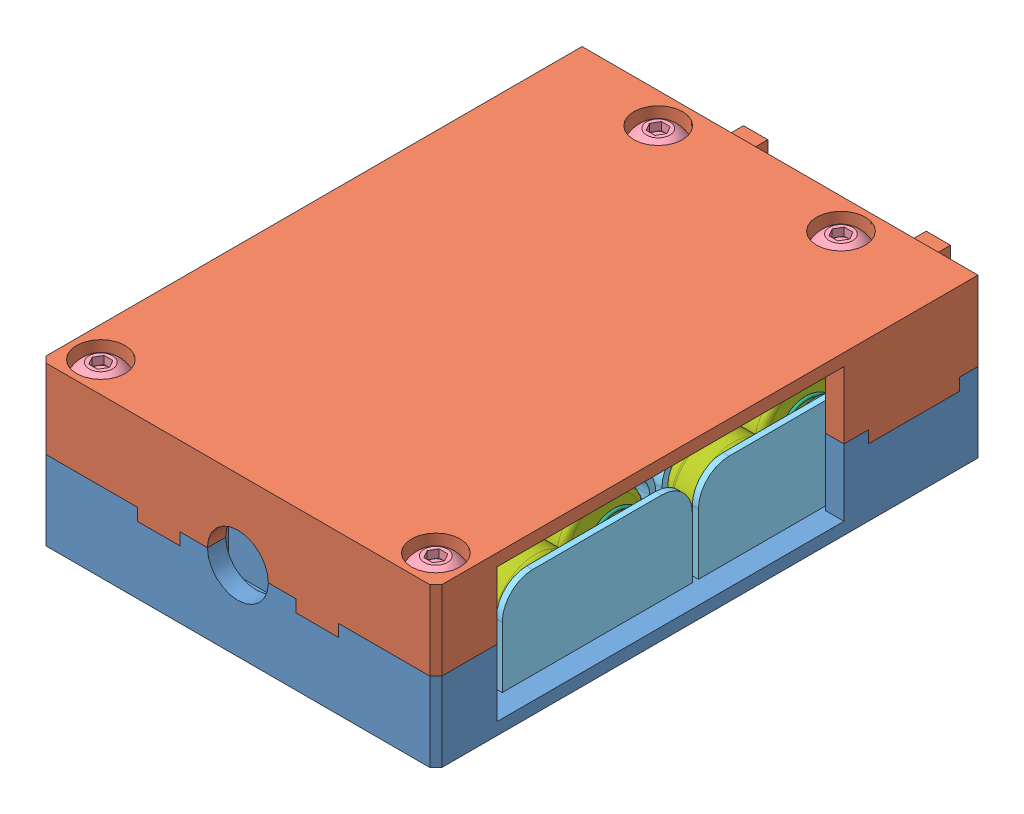
SolidWorks assembly lastro, configuration Default. Lengths in mm.
Overall size (65 26 100).
17 component instances, 7 part files, 33 mates.
Components (placement in the parent):
- chassi_lastro_inf-1: chassi_lastro_inf [Default] at origin size (65 13 100)
- chassi_lastro_sup-1: chassi_lastro_sup [Default] at (0 26 0) x (-1 0 0) z (0 0 1) size (65 15 100)
- SUB9_macho-1: SUB9_macho [Default] at (0 6.5 -44) x (-1 0 0) z (0 0 -1) size (31 12.5 11.5)
- Socket Button Head Screw_ISO-1: Socket Button Head Screw_ISO [ISO 7380 - M4 x 16 --- 16N] at (-27.5 25.6 40) x (0 -1 0) z (0 0 1) size (18.2 7.6 7.6)
- Socket Button Head Screw_ISO-2: Socket Button Head Screw_ISO [ISO 7380 - M4 x 16 --- 16N] at (27.5 25.6 40) x (0 -1 0) z (0 0 1) size (18.2 7.6 7.6)
- Socket Button Head Screw_ISO-3: Socket Button Head Screw_ISO [ISO 7380 - M4 x 16 --- 16N] at (15 25.6 -39) x (0 -1 0) z (0 0 1) size (18.2 7.6 7.6)
- Socket Button Head Screw_ISO-4: Socket Button Head Screw_ISO [ISO 7380 - M4 x 16 --- 16N] at (-15 25.6 -39) x (0 -1 0) z (0 0 1) size (18.2 7.6 7.6)
- suporte_AAx2-1: suporte_AAx2 [Default] at (28.8 3.0594 -13.6977) x (0 0 1) z (-1 0 0) size (31.2 15 57.6)
- suporte_AAx2-2: suporte_AAx2 [Default] at (28.8 3.0594 18.5023) x (0 0 1) z (-1 0 0) size (31.2 15 57.6)
- mola-1: mola [Default] at (-20.8 9.6862 22.7322) x (0 0 1) z (-1 0 0) size (28 13 7.25)
- mola-2: mola [Default] at (20.8 9.9125 -24.6023) x (0 0 -1) z (1 0 0) size (28 13 7.25)
- mola-3: mola [Default] at (-20.8 9.3925 -9.7782) x (0 0 1) z (-1 0 0) size (28 13 7.25)
- mola-4: mola [Default] at (20.8 9.6881 6.9437) x (0 0 -1) z (1 0 0) size (28 13 7.25)
- AA_battery-1: AA_battery [Default] at (27.55 9.6862 22.7322) x (0 0.291366 -0.956612) z (-1 0 0) size (14 14 50.5)
- AA_battery-2: AA_battery [Default] at (-27.55 9.3925 -24.7782) x (0 -0.149749 0.988724) z (1 0 0) size (14 14 50.5)
- AA_battery-3: AA_battery [Default] at (27.55 9.3925 -9.7782) x (0 0 1) z (-1 0 0) size (14 14 50.5)
- AA_battery-4: AA_battery [Default] at (-27.55 9.6862 7.7322) x (0 -0.891155 -0.4537) z (1 0 0) size (14 14 50.5)
Mates (geometry in assembly coordinates):
- Coincident1: coincident anti-aligned: plane of chassi_lastro_inf-1 through (-32.5 13 35) normal (0 1 0); plane of chassi_lastro_sup-1 through (-32.5 13 35) normal (0 -1 0)
- Coincident2: coincident aligned: plane of chassi_lastro_inf-1 through (-32.5 2 45) normal (0 0 1); plane of chassi_lastro_sup-1 through (32.5 24 45) normal (0 0 1)
- Coincident3: coincident anti-aligned: plane of chassi_lastro_inf-1 through (-9.5 13 45) normal (-1 0 0); plane of chassi_lastro_sup-1 through (-9.5 11 45) normal (1 0 0)
- Coincident4: coincident anti-aligned: plane of chassi_lastro_inf-1 through (-13 9 -44) normal (0 0 -1); plane of SUB9_macho-1 through (15.5 0.25 -44) normal (0 0 1)
- Concentric1: concentric aligned: cylinder of chassi_lastro_inf-1; cylinder of SUB9_macho-1
- Concentric2: concentric aligned: cylinder of chassi_lastro_inf-1; cylinder of SUB9_macho-1
- Concentric31: concentric aligned: unknown of chassi_lastro_sup-1
- Coincident51: coincident anti-aligned: unknown of chassi_lastro_sup-1
- Concentric41: concentric aligned: unknown of chassi_lastro_sup-1
- Coincident61: coincident anti-aligned: unknown of chassi_lastro_sup-1
- Concentric51: concentric aligned: unknown of chassi_lastro_sup-1
- Coincident71: coincident anti-aligned: unknown of chassi_lastro_sup-1
- Concentric61: concentric aligned: unknown of chassi_lastro_sup-1
- Coincident81: coincident anti-aligned: unknown of chassi_lastro_sup-1
- Coincident9: coincident anti-aligned: plane of chassi_lastro_inf-1 through (-32.5 2 45) normal (0 1 0); plane of suporte_AAx2-1 through (-28.8 2 -33) normal (0 -1 0)
- Coincident10: coincident anti-aligned: plane of chassi_lastro_inf-1 through (-32.5 2 45) normal (0 1 0); plane of suporte_AAx2-2 through (-28.8 2 -0.8) normal (0 -1 0)
- Distance1: distance = 1 mm anti-aligned: plane of chassi_lastro_inf-1 through (-20 13 -34) normal (0 0 1); plane of suporte_AAx2-1 through (-28.8 17 -33) normal (0 0 -1)
- Width1: width: plane of chassi_lastro_inf-1 through (-32.5 2 -45) normal (-1 0 0); plane of chassi_lastro_inf-1 through (32.5 2 -45) normal (1 0 0); plane of suporte_AAx2-1 through (28.8 2 -33) normal (1 0 0); plane of suporte_AAx2-1 through (-28.8 2 -33) normal (-1 0 0)
- Coincident12: coincident anti-aligned: plane of chassi_lastro_inf-1 through (-32.5 2 45) normal (0 1 0); plane of suporte_AAx2-2 through (-28.8 2 -0.8) normal (0 -1 0)
- Distance2: distance = 1 mm anti-aligned: plane of suporte_AAx2-1 through (-28.8 17 -1.8) normal (0 0 1); plane of suporte_AAx2-2 through (-28.8 17 -0.8) normal (0 0 -1)
- Coincident14: coincident aligned: plane of suporte_AAx2-1 through (-28.8 2 -33) normal (-1 0 0); plane of suporte_AAx2-2 through (-28.8 2 -0.8) normal (-1 0 0)
- Coincident82: coincident anti-aligned: plane of suporte_AAx2-2 through (-27.8 2 -0.8) normal (1 0 0); plane of mola-1 through (-27.8 9.6862 22.7322) normal (-1 0 0)
- Coincident83: coincident anti-aligned: plane of suporte_AAx2-2 through (27.8 2 -0.8) normal (-1 0 0); plane of mola-4 through (27.8 9.6881 6.9437) normal (1 0 0)
- Coincident85: coincident anti-aligned: plane of suporte_AAx2-1 through (27.8 2 -33) normal (-1 0 0); plane of mola-2 through (27.8 9.9125 -24.6023) normal (1 0 0)
- Coincident86: coincident anti-aligned: plane of suporte_AAx2-1 through (-27.8 2 -33) normal (1 0 0); plane of mola-3 through (-27.8 9.3925 -9.7782) normal (-1 0 0)
- Concentric62: concentric anti-aligned: cylinder of mola-1; cylinder of AA_battery-1
- Concentric64: concentric aligned: cylinder of ?; cylinder of ?
- Concentric65: concentric anti-aligned: cylinder of mola-3; cylinder of AA_battery-3
- Concentric66: concentric: cylinder of ?; cylinder of ?
- Coincident88: coincident anti-aligned: plane of mola-4 through (27.55 9.6881 6.9437) normal (-1 0 0); plane of AA_battery-1 through (27.55 9.6862 22.7322) normal (1 0 0)
- Coincident90: coincident anti-aligned: plane of mola-2 through (27.55 9.9125 -24.6023) normal (-1 0 0); plane of AA_battery-3 through (27.55 9.3925 -9.7782) normal (1 0 0)
- Coincident91: coincident anti-aligned: plane of ?; plane of ?
- Coincident92: coincident anti-aligned: plane of ?; plane of ?
